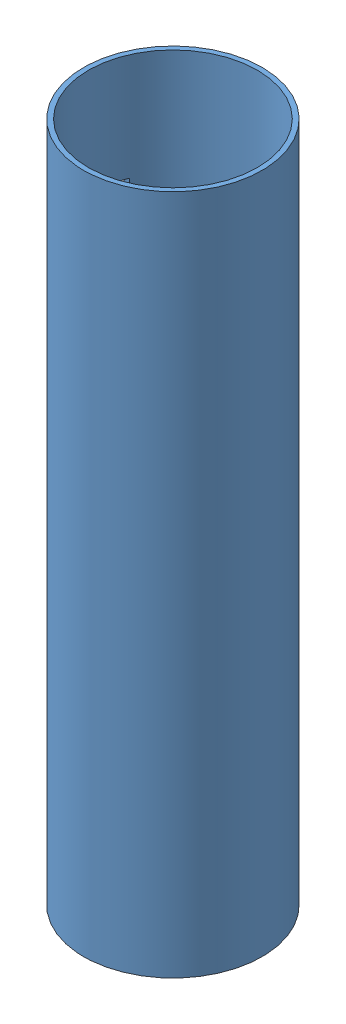
SolidWorks assembly sleeve, configuration Default. Lengths in mm.
Overall size (94.17 359.16 94.17).
2 component instances, 2 part files, 1 mates.
Components (placement in the parent):
- Part111-1: Part111 [Default] at (169.4305 54.6072 347.2561) size (94.17 359.16 94.17)
- Part222-2: Part222 [Default] at (126.7546 279.671 363.2805) x (0.144437 0.042647 0.988595) z (-0.006165 0.99909 -0.042199) size (25.4 8.38 93.39)
Mates (geometry in assembly coordinates):
- Tangent7: tangent aligned: cylinder of Part111-1 through (169.4305 413.7632 347.2561) axis (0 -1 0) radius 44.5442; plane of Part222-2 through (126.7546 279.671 363.2805) normal (-0.989495 0 0.144568)
